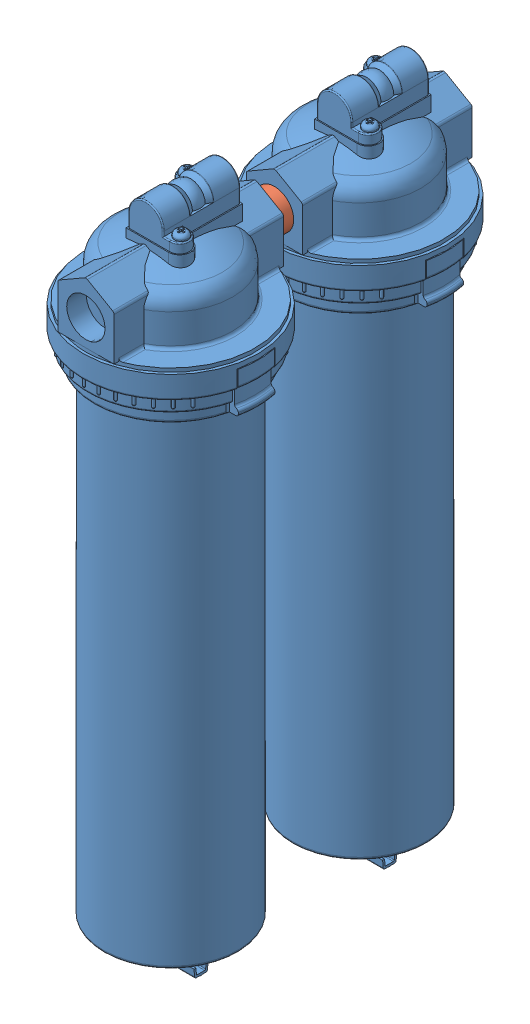
SolidWorks assembly ReadingTech_4P-090-M06-DCPi, configuration Default. Lengths in mm.
Overall size (121.86 464.6 252.73).
3 component instances, 2 part files, 3 mates.
Components (placement in the parent):
- ReadingTech_3P-090-M06-Pi-1: ReadingTech_3P-090-M06-Pi [Default] at (-4.9908 -190.5523 -7.8343) size (121.86 464.6 121.67)
- ReadingTech_3P-090-M06-Pi-2: ReadingTech_3P-090-M06-Pi [Default] at (-4.9908 -190.5523 -138.8983) size (121.86 464.6 121.67)
- ReadingTech- 90,150cfm_connector_.75in-1: ReadingTech- 90,150cfm_connector_.75in [Default] at (-4.9908 198.4487 -66.7623) x (-0.923728 -0.383049 0) z (0.383049 -0.923728 0) size (26.67 13.21 26.67)
Mates (geometry in assembly coordinates):
- Coincident1: coincident aligned: circle of ReadingTech_3P-090-M06-Pi-1; circle of ReadingTech- 90,150cfm_connector_.75in-1
- Coincident2: coincident anti-aligned: circle of ReadingTech_3P-090-M06-Pi-2; circle of ReadingTech- 90,150cfm_connector_.75in-1
- Coincident3: coincident aligned: plane of ReadingTech_3P-090-M06-Pi-1 through (14.5672 211.1487 51.0937) normal (1 0 0); plane of ReadingTech_3P-090-M06-Pi-2 through (14.5672 211.1487 -79.9703) normal (1 0 0)
